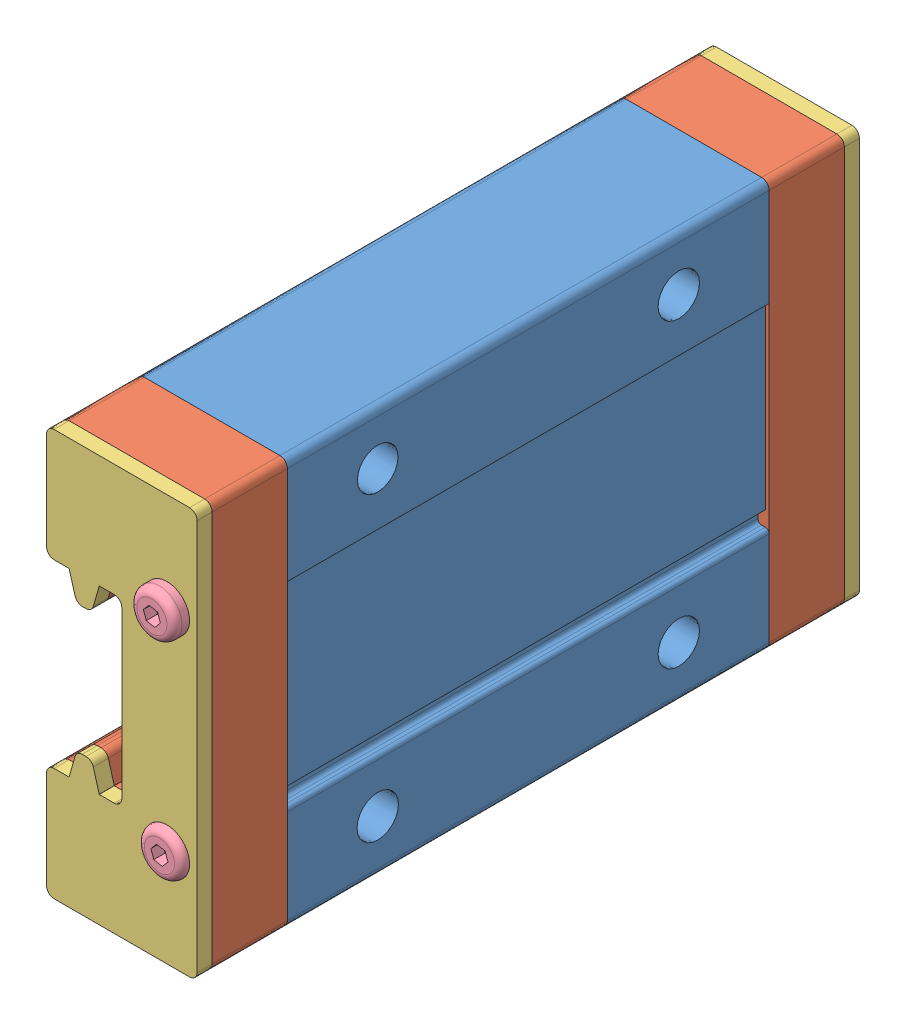
SolidWorks assembly Assieme Guida e Carrello, configuration Default. Lengths in mm.
Overall size (10 27 45.5).
10 component instances, 5 part files, 26 mates.
Components (placement in the parent):
- Main Block-1: Main Block [Default] at (169.1827 226.6144 392.7481) x (0 0 1) z (1 0 0) size (32 27 10)
- Green End Cap-1: Green End Cap [Default] at (174.1827 226.6144 376.7481) x (0 1 0) z (0 0 -1) size (27 10 5)
- Red End Cap-1: Red End Cap [Default] at (174.1827 226.6144 371.7481) x (0 1 0) z (0 0 -1) size (27 10 1)
- Green End Cap-2: Green End Cap [Default] at (174.1827 226.6144 408.7481) x (0 -1 0) z (0 0 1) size (27 10 5)
- Red End Cap-2: Red End Cap [Default] at (174.1827 226.6144 413.7481) x (0 -1 0) z (0 0 1) size (27 10 1)
- Button M3x8-1: Button M3x8 [Default] at (177.1827 219.6144 415.2481) x (0.381849 -0.924225 0) z (0 0 -1) size (3 3 7)
- Button M3x8-2: Button M3x8 [Default] at (177.1827 233.6144 415.7481) x (0.381849 -0.924225 0) z (0 0 -1) size (3 3 7)
- Button M3x8-3: Button M3x8 [Default] at (177.1827 219.6144 370.2481) x (-0.381849 0.924225 0) z (0 0 1) size (3 3 7)
- Button M3x8-5: Button M3x8 [Default] at (177.1827 233.6144 370.2481) x (-0.381849 0.924225 0) z (0 0 1) size (3 3 7)
- Rail 300mm-3: Rail 300mm [Default] at (170.1827 226.6144 554.048) x (0 0 -1) z (1 0 0) size (300 12 8) (hidden)
Mates (geometry in assembly coordinates):
- Coincident1: coincident: plane of ? through (405.2255 225.8015 379.5515) normal (0 0 1); plane of ? through (174.1827 220.6144 414.0095) normal (-1 0 0)
- Coincident2: coincident: plane of ? through (405.2255 225.8015 379.5515) normal (0 1 0); plane of ? through (172.6827 220.6144 414.0095) normal (0 1 0)
- Coincident3: coincident anti-aligned: plane of Main Block-1 through (179.1827 213.1144 376.7481) normal (0 0 -1); plane of Green End Cap-1 through (174.1827 226.6144 376.7481) normal (0 0 1)
- Coincident4: coincident aligned: plane of Main Block-1 through (179.1827 240.1144 376.7481) normal (0 1 0); plane of Green End Cap-1 through (179.1827 240.1144 371.7481) normal (0 1 0)
- Coincident5: coincident aligned: plane of Main Block-1 through (169.1827 226.6144 392.7481) normal (-1 0 0); plane of Green End Cap-1 through (169.1827 232.6144 371.7481) normal (-1 0 0)
- Coincident9: coincident anti-aligned: plane of Main Block-1 through (179.1827 213.1144 408.7481) normal (0 0 1); plane of Green End Cap-2 through (174.1827 226.6144 408.7481) normal (0 0 -1)
- Coincident10: coincident aligned: plane of Main Block-1 through (179.1827 240.1144 376.7481) normal (0 1 0); plane of Green End Cap-2 through (179.1827 240.1144 413.7481) normal (0 1 0)
- Coincident11: coincident aligned: plane of Main Block-1 through (179.1827 226.6144 392.7481) normal (1 0 0); plane of Green End Cap-2 through (179.1827 240.1144 413.7481) normal (1 0 0)
- Coincident12: coincident anti-aligned: plane of Green End Cap-2 through (174.1827 226.6144 413.7481) normal (0 0 1); plane of Red End Cap-2 through (174.1827 226.6144 413.7481) normal (0 0 -1)
- Coincident13: coincident aligned: plane of Green End Cap-2 through (179.1827 240.1144 413.7481) normal (0 1 0); plane of Red End Cap-2 through (179.1827 240.1144 414.7481) normal (0 1 0)
- Coincident14: coincident aligned: plane of Green End Cap-2 through (179.1827 240.1144 413.7481) normal (1 0 0); plane of Red End Cap-2 through (179.1827 240.1144 414.7481) normal (1 0 0)
- Coincident16: coincident anti-aligned: plane of Green End Cap-1 through (174.1827 226.6144 371.7481) normal (0 0 -1); plane of Red End Cap-1 through (174.1827 226.6144 371.7481) normal (0 0 1)
- Coincident17: coincident aligned: plane of Green End Cap-1 through (179.1827 213.1144 371.7481) normal (0 -1 0); plane of Red End Cap-1 through (179.1827 213.1144 370.7481) normal (0 -1 0)
- Coincident18: coincident aligned: plane of Green End Cap-1 through (169.1827 213.1144 371.7481) normal (-1 0 0); plane of Red End Cap-1 through (169.1827 213.1144 370.7481) normal (-1 0 0)
- Concentric1: concentric aligned: cylinder of Green End Cap-1 through (177.1827 219.6144 376.7481) axis (0 0 -1) radius 1; cylinder of Button M3x8-3 through (177.1827 219.6144 377.2481) axis (0 0 -1) radius 1
- Coincident19: coincident anti-aligned: plane of Red End Cap-1 through (177.1827 219.6144 371.2481) normal (0 0 -1); plane of Button M3x8-3 through (177.1827 219.6144 371.2481) normal (0 0 1)
- Concentric2: concentric aligned: cylinder of Green End Cap-1 through (177.1827 233.6144 376.7481) axis (0 0 -1) radius 1; cylinder of Button M3x8-5 through (177.1827 233.6144 377.2481) axis (0 0 -1) radius 1
- Coincident20: coincident anti-aligned: plane of Red End Cap-1 through (177.1827 233.6144 371.2481) normal (0 0 -1); plane of Button M3x8-5 through (177.1827 233.6144 371.2481) normal (0 0 1)
- Concentric3: concentric aligned: cylinder of Green End Cap-2 through (177.1827 219.6144 408.7481) axis (0 0 1) radius 1; cylinder of Button M3x8-1 through (177.1827 219.6144 408.2481) axis (0 0 1) radius 1
- Coincident21: coincident anti-aligned: plane of Red End Cap-2 through (177.1827 219.6144 414.2481) normal (0 0 1); plane of Button M3x8-1 through (177.1827 219.6144 414.2481) normal (0 0 -1)
- Concentric4: concentric aligned: cylinder of Green End Cap-2 through (177.1827 233.6144 408.7481) axis (0 0 1) radius 1; cylinder of Button M3x8-2 through (177.1827 233.6144 408.7481) axis (0 0 1) radius 1
- Coincident22: coincident anti-aligned: plane of Red End Cap-2 through (174.1827 226.6144 414.7481) normal (0 0 1); plane of Button M3x8-2 through (177.1827 233.6144 414.7481) normal (0 0 -1)
- Coincident24: coincident anti-aligned: plane of Main Block-1 through (174.1827 220.6144 414.0095) normal (-1 0 0); plane of ? through (166.1827 232.5585 379.9218) normal (-1 0 0)
- Coincident25: coincident anti-aligned: plane of Main Block-1 through (172.6827 232.6144 414.0095) normal (0 -1 0); plane of ? through (166.1827 220.5585 379.9218) normal (0 -1 0)
- Coincident27: coincident anti-aligned: plane of Main Block-1 through (174.1827 220.6144 413.7481) normal (-1 0 0); plane of Rail 300mm-3 through (174.1827 232.6144 254.048) normal (1 0 0)
- Coincident28: coincident anti-aligned: plane of Main Block-1 through (172.6827 232.6144 413.7481) normal (0 -1 0); plane of Rail 300mm-3 through (174.1827 232.6144 254.048) normal (0 1 0)
